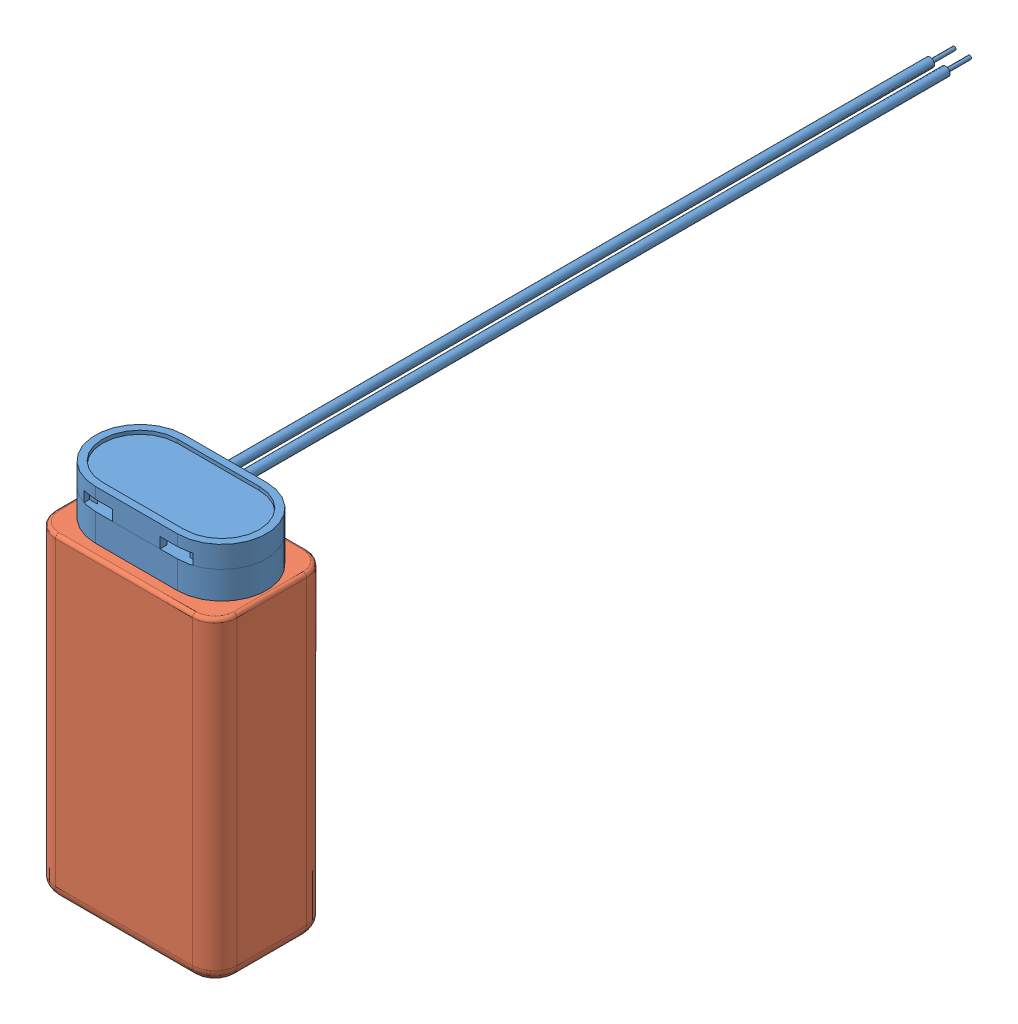
SolidWorks assembly panelHostedBattery, configuration Default. Lengths in mm.
Overall size (30.63 76.84 119.51).
31 component instances, 17 part files, 8 mates.
Components (placement in the parent):
- panelHostedBatteryCompartment-1: panelHostedBatteryCompartment [Default] at origin size (40.9 86.4 25.1)
  - lidPocket^panelHostedBatteryCompartment-1: lidPocket^panelHostedBatteryCompartment [Default] at origin size (34.9 80.4 3.6) (hidden, virtual)
  - lid^panelHostedBatteryCompartment-1: lid^panelHostedBatteryCompartment [Default] at origin size (33.5 79 3.3) (hidden, virtual)
  - clampingMeatForLidMountHoles^panelHostedBatteryCompartment-1: clampingMeatForLidMountHoles^panelHostedBatteryCompartment [Default] at origin size (33.5 79 15) (hidden, virtual)
  - lidMountingPilotHoles^panelHostedBatteryCompartment-1: lidMountingPilotHoles^panelHostedBatteryCompartment [Default] at origin size (24.6 70.1 18.6) (hidden, virtual)
  - batteryCavity^panelHostedBatteryCompartment-1: batteryCavity^panelHostedBatteryCompartment [Default] at origin size (27.5 55 18.5) (hidden, virtual)
  - shell^panelHostedBatteryCompartment-1: shell^panelHostedBatteryCompartment [Default] at origin size (40.9 86.4 25.1) (hidden, virtual)
  - wireHoles^panelHostedBatteryCompartment-1: wireHoles^panelHostedBatteryCompartment [Default] at origin size (2.2 61 2.2) (hidden, virtual)
  - embeddableNut-1: embeddableNut [Default] at (-10.75 -33.5 -8.08) x (0.305549 0.952176 0) z (0 0 1) size (8.08 7 3.75) (hidden)
    - nut^embeddableNut-1: nut^embeddableNut [Default] at origin size (8.08 7 3.75) (virtual)
    - nutCave^embeddableNut-1: nutCave^embeddableNut [Default] at origin size (35 7.8 4.2) (hidden, virtual)
    - embedmentCylinder^embeddableNut-1: embedmentCylinder^embeddableNut [Default] at origin size (14 14 8.96) (hidden, virtual)
  - embeddableNut-2: embeddableNut [Default] at (10.75 -33.5 -8.08) x (-0.305549 0.952176 0) z (0 0 1) size (8.08 7 3.75) (hidden)
    - nut^embeddableNut-1: nut^embeddableNut [Default] at origin size (8.08 7 3.75) (virtual)
    - nutCave^embeddableNut-1: nutCave^embeddableNut [Default] at origin size (35 7.8 4.2) (hidden, virtual)
    - embedmentCylinder^embeddableNut-1: embedmentCylinder^embeddableNut [Default] at origin size (14 14 8.96) (hidden, virtual)
  - embeddableNut-3: embeddableNut [Default] at (10.75 33.5 -8.08) x (-0.305549 -0.952176 0) z (0 0 1) size (8.08 7 3.75) (hidden)
    - nut^embeddableNut-1: nut^embeddableNut [Default] at origin size (8.08 7 3.75) (virtual)
    - nutCave^embeddableNut-1: nutCave^embeddableNut [Default] at origin size (35 7.8 4.2) (hidden, virtual)
    - embedmentCylinder^embeddableNut-1: embedmentCylinder^embeddableNut [Default] at origin size (14 14 8.96) (hidden, virtual)
  - embeddableNut-4: embeddableNut [Default] at (-10.75 33.5 -8.08) x (0.305549 -0.952176 0) z (0 0 1) size (8.08 7 3.75) (hidden)
    - nut^embeddableNut-1: nut^embeddableNut [Default] at origin size (8.08 7 3.75) (virtual)
    - nutCave^embeddableNut-1: nutCave^embeddableNut [Default] at origin size (35 7.8 4.2) (hidden, virtual)
    - embedmentCylinder^embeddableNut-1: embedmentCylinder^embeddableNut [Default] at origin size (14 14 8.96) (hidden, virtual)
  - screwClearanceHolesForEmbeddableNuts^panelHostedBatteryCompartment-1: screwClearanceHolesForEmbeddableNuts^panelHostedBatteryCompartment [Default] at origin size (25.85 71.35 18.6) (hidden, virtual)
  - panelAddition^panelHostedBatteryCompartment-1: panelAddition^panelHostedBatteryCompartment [Default] at origin size (40.9 86.4 25.1) (hidden, virtual)
  - panelSubtraction^panelHostedBatteryCompartment-1: panelSubtraction^panelHostedBatteryCompartment [Default] at origin size (34.9 80.4 22.1) (hidden, virtual)
- keystone-PN81-8-1: keystone-PN81-8 [Default] at (6.3362 9.6919 -55.6752) x (1 0 0) z (0 0 -1) size (24.38 8.16 117.73)
- Battery 9V-1: Battery 9V [Default] at (1.2115 -20.0192 -27.8481) size (25.91 48.13 16.26)
- panelAddition^panelHostedBattery-1: panelAddition^panelHostedBattery [Default] at origin size (40.9 86.4 25.1) (hidden, virtual)
- panelSubtraction^panelHostedBattery-1: panelSubtraction^panelHostedBattery [Default] at origin size (34.9 80.4 22.1) (hidden, virtual)
Mates (geometry in assembly coordinates):
- Coincident10: coordinate: point of keystone-PN81-8-1; point of Battery 9V-1
- Coincident11: coordinate: unknown of ?
- Coincident12: coincident anti-aligned: plane of ? through (0 0 -22.1) normal (0 0 1); plane of Battery 9V-1 through (-12.954 17.712 -22.1) normal (0 0 -1)
- Coincident13: coincident: plane of ? through (0 0 0) normal (1 0 0); moEndPointRef_w of Battery 9V-1
- Parallel1: parallel aligned: line of Battery 9V-1 through (1.2115 -70.0192 -27.8481) axis (0 1 0); line of assembly
- Coincident15: coincident: plane of ? through (0 -27.5 0) normal (0 1 0); point of Battery 9V-1
- Coincident16: coordinate: unknown of ?
- Coincident17: coordinate: unknown of ?
